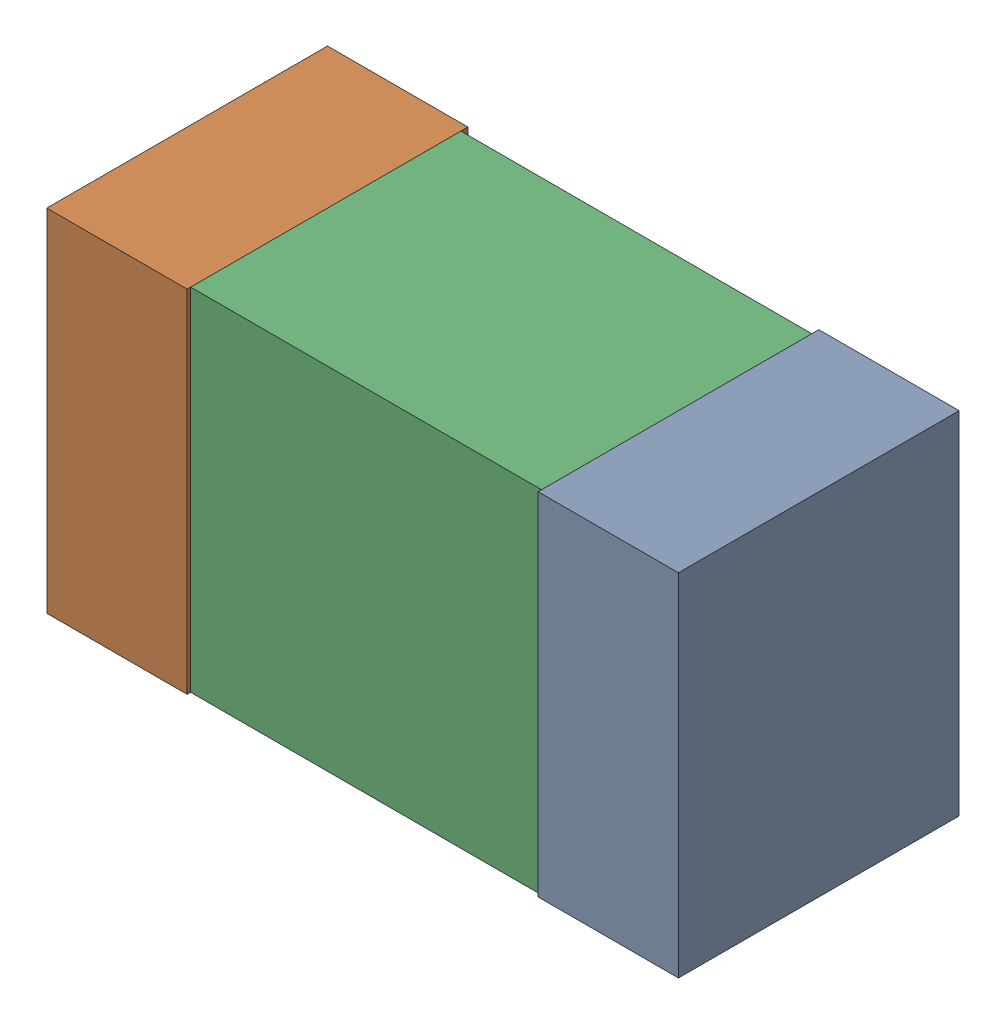
SolidWorks assembly L407PCB, configuration Default. Lengths in mm.
Overall size (1.8 1 0.8).
6 component instances, 2 part files, 0 mates.
Components (placement in the parent):
- 854785840-1: 854785840 [Default] at (86.6001 85.2999 -2.4638) size (0.4 1 0.8)
  - Extruded_4-1: Extruded_4 [Default] at origin size (0.4 1 0.8)
- 854785840-2: 854785840 [Default] at (85.2001 85.2999 -2.4638) size (0.4 1 0.8)
  - Extruded_4-1: Extruded_4 [Default] at origin size (0.4 1 0.8)
- 846483152-1: 846483152 [Default] at (85.9001 85.2999 -2.4438) size (1 1 0.77)
  - Extruded_3-1: Extruded_3 [Default] at origin size (1 1 0.77)
